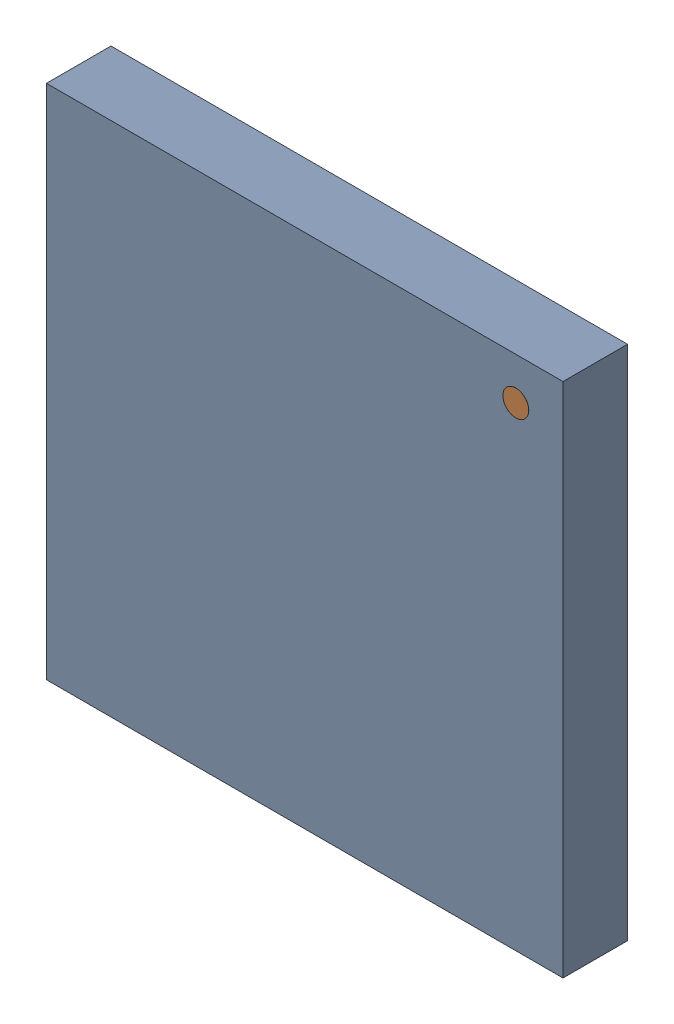
SolidWorks assembly U2, configuration 默认. Lengths in mm.
Overall size (8 8 1).
4 component instances, 2 part files, 0 mates.
Components (placement in the parent):
- 6641437328-1: 6641437328 [默认] at (8.169 10.388 0) size (8 8 1)
  - Extruded-26-1: Extruded-26 [默认] at origin size (8 8 1)
- 6641437008-1: 6641437008 [默认] at (11.439 13.736 0) x (0 -1 0) z (0 0 1) size (0.4 0.4 1)
  - Cylinder-27-1: Cylinder-27 [默认] at origin size (0.4 0.4 1)
